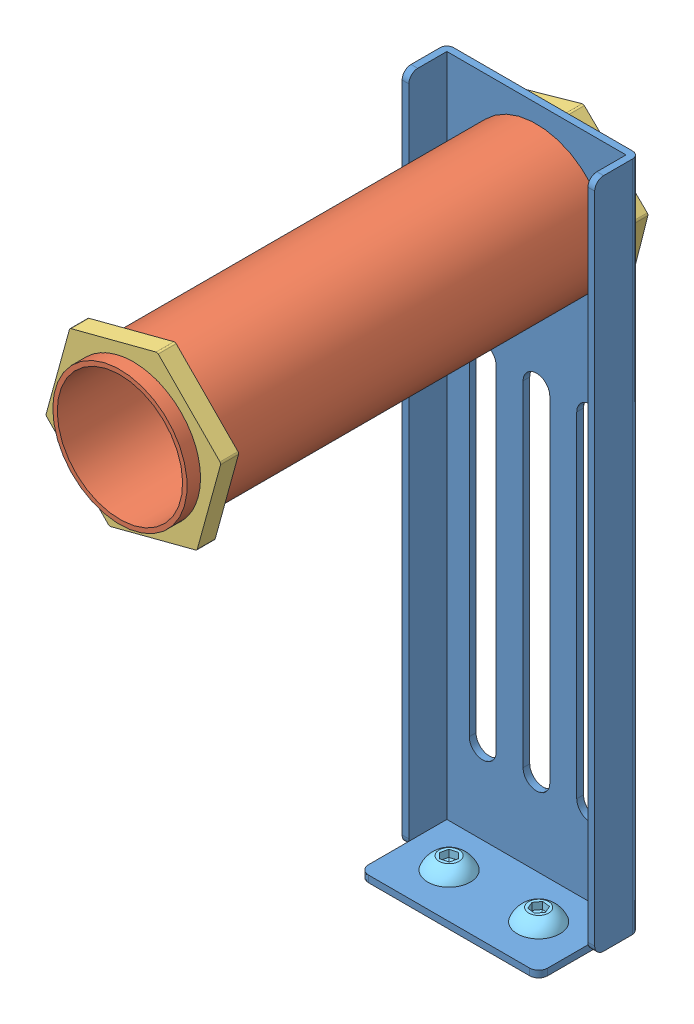
SolidWorks assembly ASM Spool Holder, configuration Standard. Lengths in mm.
Overall size (44.62 160.55 100).
8 component instances, 5 part files, 19 mates.
Components (placement in the parent):
- Support frame-1: Support frame [Standard] x (0 0 1) z (0 1 0) size (21 43 150)
- Support tube-1: Support tube [Standard] at (20 130 94.5) x (-0.815067 -0.579367 0) z (0.579367 -0.815067 0) size (32 100 32)
- M30 Plastic nut-1: M30 Plastic nut [Standard] at (20 130 0) x (0.246837 0.969057 0) z (-0.969057 0.246837 0) size (40.26 4 35)
- M30 Plastic nut-2: M30 Plastic nut [Standard] at (20 130 87.5) x (0.264888 0.964279 0) z (0.964279 -0.264888 0) size (40.26 4 35)
- M4 T-Slot Nut-1: M4 T-Slot Nut [Standard] at (30 -2.6373 11) x (1 0 0) z (0 -1 0) size (6 9.5 4.1)
- M4 T-Slot Nut-2: M4 T-Slot Nut [Standard] at (10 -2.6373 11) x (1 0 0) z (0 -1 0) size (6 9.5 4.1)
- M5X8Pan Head Screw-1: M5X8Pan Head Screw [Standard] at (30 4.25 11) x (0 -1 0) z (0.397163 0 0.917748) size (11.26 10.04 9.97)
- M5X8Pan Head Screw-2: M5X8Pan Head Screw [Standard] at (10 4.25 11) x (0 -1 0) z (0.724949 0 0.688802) size (11.26 10.04 9.97)
Mates (geometry in assembly coordinates):
- Konzentrisch75: concentric aligned: cylinder of Support frame-1 through (10 1.5 59.2887) axis (0 1 0) radius 2.7134; cylinder of M4 T-Slot Nut-2 through (10 -5.5663 59.2887) axis (0 1 0) radius 2
- Konzentrisch76: concentric aligned: cylinder of Support frame-1 through (30 1.5 59.2887) axis (0 1 0) radius 2.7134; cylinder of M4 T-Slot Nut-1 through (30 -5.5663 59.2887) axis (0 1 0) radius 2
- Konzentrisch77: concentric aligned: cylinder of Support frame-1 through (20 130 49.7887) axis (0 0 1) radius 15.2; cylinder of Support tube-1 through (20 130 42.7887) axis (0 0 1) radius 16
- Deckungsgleich87: coincident anti-aligned: plane of Support frame-1 through (39.998 2.002 49.7887) normal (0 0 1); plane of Support tube-1 through (20 130 49.7887) normal (0 0 -1)
- Deckungsgleich88: coincident anti-aligned: plane of Support frame-1 through (0 0 48.2887) normal (0 0 -1); plane of M30 Plastic nut-1 through (20 130 48.2887) normal (0 0 1)
- Konzentrisch102: concentric aligned: cylinder of Support frame-1 through (30 1.5 59.2887) axis (0 1 0) radius 2.7134; cylinder of M5X8Pan Head Screw-1 through (30 -8.5 59.2887) axis (0 1 0) radius 2.5
- Deckungsgleich114: coincident anti-aligned: plane of Support frame-1 through (0 1.5 48.2887) normal (0 1 0); plane of M5X8Pan Head Screw-1 through (30 1.5 59.2887) normal (0 -1 0)
- Konzentrisch103: concentric aligned: cylinder of Support frame-1 through (10 1.5 59.2887) axis (0 1 0) radius 2.7134; cylinder of M5X8Pan Head Screw-2 through (10 -8.5 59.2887) axis (0 1 0) radius 2.5
- Deckungsgleich115: coincident anti-aligned: plane of Support frame-1 through (0 1.5 48.2887) normal (0 1 0); plane of M5X8Pan Head Screw-2 through (10 1.5 59.2887) normal (0 -1 0)
- Konzentrisch78: concentric aligned: cylinder of Support tube-1 through (20 130 42.7887) axis (0 0 1) radius 16; cylinder of M30 Plastic nut-1 through (20 130 44.2887) axis (0 0 1) radius 15
- Konzentrisch79: concentric anti-aligned: cylinder of Support tube-1 through (20 130 135.7887) axis (0 0 1) radius 15; cylinder of M30 Plastic nut-2 through (20 130 139.7887) axis (0 0 -1) radius 15
- Deckungsgleich89: coincident anti-aligned: plane of Support tube-1 through (20 130 135.7887) normal (0 0 1); plane of M30 Plastic nut-2 through (20 130 135.7887) normal (0 0 -1)
- Parallel1: parallel aligned: plane of Support frame-1 through (40 2.002 56.2887) normal (1 0 0); plane of M4 T-Slot Nut-1 through (33 -2.6373 59.2887) normal (1 0 0)
- Parallel2: parallel aligned: plane of M4 T-Slot Nut-1 through (33 -2.6373 59.2887) normal (1 0 0); plane of M4 T-Slot Nut-2 through (13 -2.6373 59.2887) normal (1 0 0)
- Deckungsgleich116: coincident aligned: plane of M4 T-Slot Nut-1 through (33 -1.8 54.5387) normal (0 1 0); plane of M4 T-Slot Nut-2 through (13 -1.8 54.5387) normal (0 1 0)
- Abstand1: distance = 1.8 mm anti-aligned: plane of M4 T-Slot Nut-1 through (33 -1.8 6.25) normal (0 1 0); plane of Support frame-1 through (0 0 21) normal (0 -1 0)
- Deckungsgleich117: coincident aligned: plane of ? through (0 0 48.2887) normal (0 1 0)
- Deckungsgleich118: coincident aligned: unknown of ?
- Deckungsgleich119: coincident aligned: plane of Support frame-1; plane of assembly
